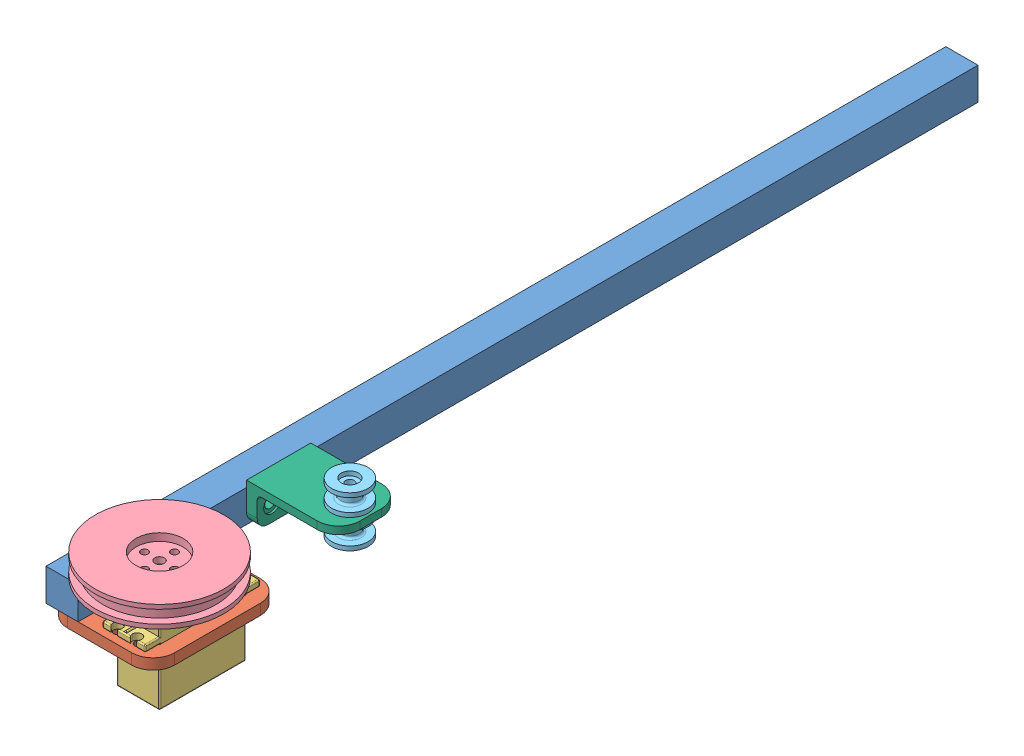
SolidWorks assembly 001_ASSY_PICKUP_BOX, configuration Default. Lengths in mm.
Overall size (63.25 54.6 430.25).
7 component instances, 6 part files, 14 mates.
Components (placement in the parent):
- ALU_15x15_420mm-1: ALU_15x15_420mm [Default] at (133.0505 248.4858 104.9943) x (1 0 0) z (0 -1 0) size (15 420 15)
- MG996 Holder-1: MG996 Holder [Default] at (150.5505 235.9858 494.9943) size (50 5 60)
- Servo MG996R.step-1: Servo MG996R.step [Default] at (168.8005 214.3858 515.2443) x (0 0 -1) z (1 0 0) size (53.62 47.6 20.01)
- Pulley_2-1: Pulley_2 [Default] at (158.8005 258.4858 505.2443) size (60 10 60)
- pulley_v3-1: pulley_v3 [Default] at (173.8005 258.9858 431.4109) size (17 10 17)
- pulley_holder_v3_2-1: pulley_holder_v3_2 [Default] at (164.5505 255.4858 431.4109) size (43 18 30)
- pulley_v3-2: pulley_v3 [Default] at (173.8005 245.4858 431.4109) size (17 10 17)
Mates (geometry in assembly coordinates):
- Coincident1: coincident: plane of assembly; plane of assembly; plane of MG996 Holder-1 through (168.8005 235.9858 515.2443) normal (0 0 -1); plane of Servo MG996R.step-1 through (168.8005 250.9858 515.2443) normal (0 0 1)
- Coincident2: coincident: plane of assembly; plane of assembly; plane of MG996 Holder-1 through (168.8005 235.9858 515.2443) normal (-1 0 0); plane of Servo MG996R.step-1 through (168.8005 250.9858 515.2443) normal (1 0 0)
- Coincident3: coincident: plane of assembly; plane of assembly; plane of MG996 Holder-1 through (150.5505 240.9858 494.9943) normal (0 1 0); plane of Servo MG996R.step-1 through (168.8005 240.9858 521.8943) normal (0 -1 0)
- Coincident4: coincident: plane of assembly; plane of assembly; plane of ALU_15x15_420mm-1 through (140.5505 240.9858 524.9943) normal (0 -1 0); plane of MG996 Holder-1 through (150.5505 240.9858 494.9943) normal (0 1 0)
- Coincident5: coincident: plane of assembly; plane of assembly; plane of ALU_15x15_420mm-1 through (125.5505 255.9858 524.9943) normal (-1 0 0); plane of MG996 Holder-1 through (125.5505 240.9858 524.9943) normal (-1 0 0)
- Coincident6: coincident: plane of assembly; plane of assembly; plane of ALU_15x15_420mm-1 through (133.0505 248.4858 524.9943) normal (0 0 1); plane of MG996 Holder-1 through (175.5505 240.9858 524.9943) normal (0 0 1)
- Concentric1: concentric: cylinder of assembly; cylinder of assembly; cylinder of Servo MG996R.step-1 through (158.8005 254.0858 505.2443) axis (0 -1 0) radius 6; cylinder of Pulley_2-1 through (158.8005 252.4858 505.2443) axis (0 1 0) radius 2.25
- Coincident7: coincident: plane of assembly; plane of assembly; plane of Servo MG996R.step-1 through (158.8005 261.9858 505.2443) normal (0 1 0); plane of Pulley_2-1 through (158.8005 261.9858 505.2443) normal (0 -1 0)
- Coincident17: coincident: plane of assembly; plane of assembly; plane of ALU_15x15_420mm-1 through (140.5505 255.9858 524.9943) normal (1 0 0); plane of pulley_holder_v3_2-1 through (140.5505 255.4858 431.4109) normal (-1 0 0)
- Coincident18: coincident: plane of assembly; plane of assembly; plane of ALU_15x15_420mm-1 through (140.5505 240.9858 524.9943) normal (0 -1 0); plane of pulley_holder_v3_2-1 through (140.5505 240.9858 416.4109) normal (0 -1 0)
- Concentric5: concentric: cylinder of assembly; cylinder of assembly; cylinder of pulley_v3-1 through (173.8005 255.9858 431.4109) axis (0 1 0) radius 2; cylinder of pulley_holder_v3_2-1 through (173.8005 253.9858 431.4109) axis (0 1 0) radius 2.5
- Coincident19: coincident: plane of assembly; plane of assembly; plane of pulley_v3-1 through (173.8005 258.9858 431.4109) normal (0 -1 0); plane of pulley_holder_v3_2-1 through (164.5505 258.9858 431.4109) normal (0 1 0)
- Concentric6: concentric: cylinder of assembly; cylinder of assembly; cylinder of pulley_holder_v3_2-1 through (173.8005 253.9858 431.4109) axis (0 1 0) radius 2.5; cylinder of pulley_v3-2 through (173.8005 253.4858 431.4109) axis (0 1 0) radius 4
- Coincident20: coincident: plane of assembly; plane of assembly; plane of pulley_holder_v3_2-1 through (164.5505 255.4858 431.4109) normal (0 -1 0); plane of pulley_v3-2 through (173.8005 255.4858 431.4109) normal (0 1 0)
